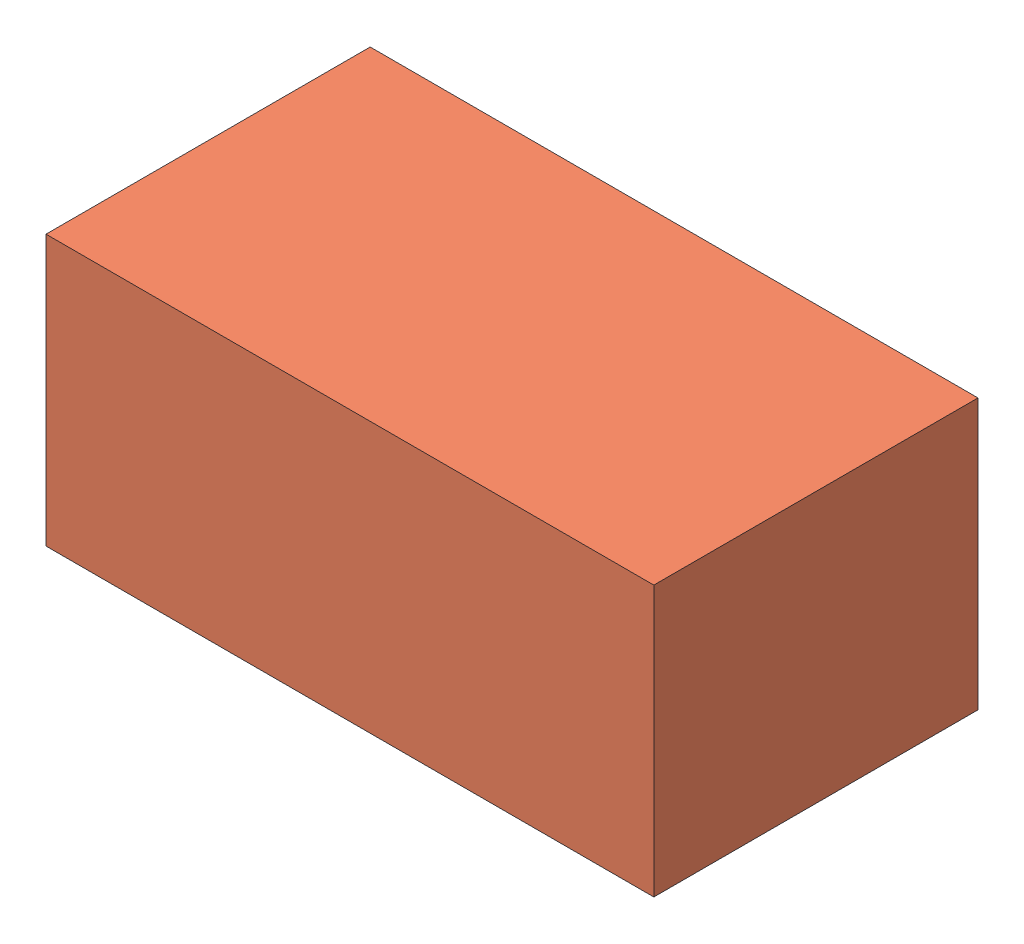
SolidWorks assembly Assem1, configuration Default. Lengths in mm.
Overall size (450.01 200.01 240.01).
3 component instances, 2 part files, 0 mates.
Components (placement in the parent):
- MyShip-1: MyShip [Default] at (73.5235 167.1443 196.2487) size (450.01 200.01 240.01)
  - Example_MakeCfdShipCase1_1-1: Example_MakeCfdShipCase1_1 [Default] at (-192.3726 74.5542 136.8557) size (160.03 25.03 18.01)
  - Example_MakeCfdShipCase1_2-1: Example_MakeCfdShipCase1_2 [Default] at (-123.7452 73.3953 141.7111) size (450.01 200.01 240.01)
